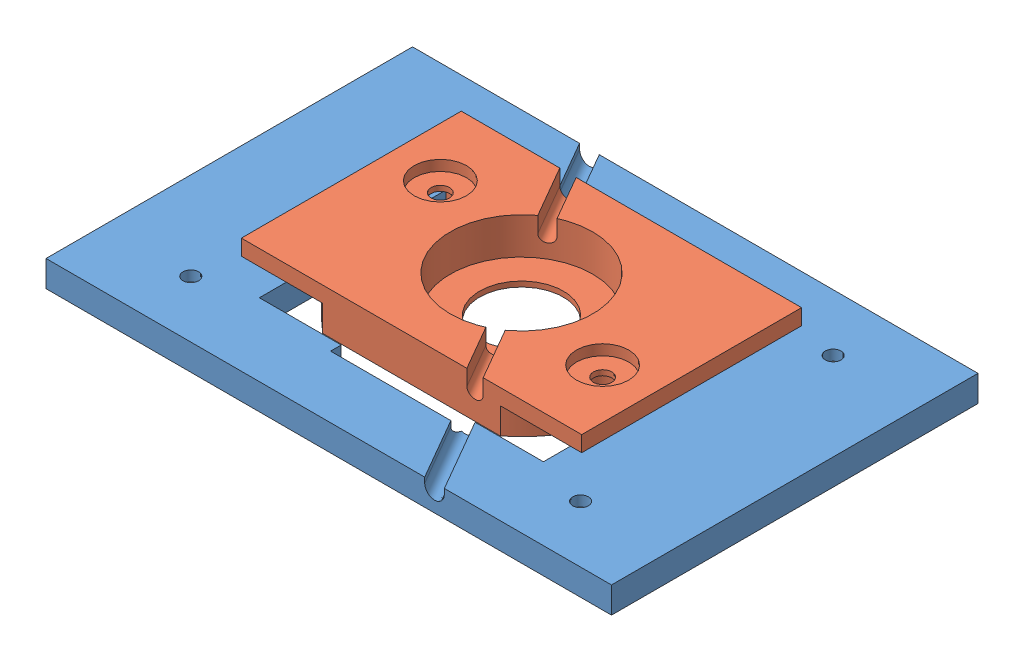
SolidWorks assembly bioreact holder+clamp base, configuration Default. Lengths in mm.
Overall size (108 11.54 70).
2 component instances, 2 part files, 1 mates.
Components (placement in the parent):
- Bioreactor holder-1: Bioreactor holder [Default] at (-29.8672 -32.6383 0) size (108 5 70)
- mycroscope clamp base-1: mycroscope clamp base [Default] at (-29.5358 -29.0964 -1.4796) size (65 8 42)
Mates (geometry in assembly coordinates):
- Coincidente1: coincident: moEndPointRef_w of Bioreactor holder-1; moEndPointRef_w of Bioreactor holder-1
